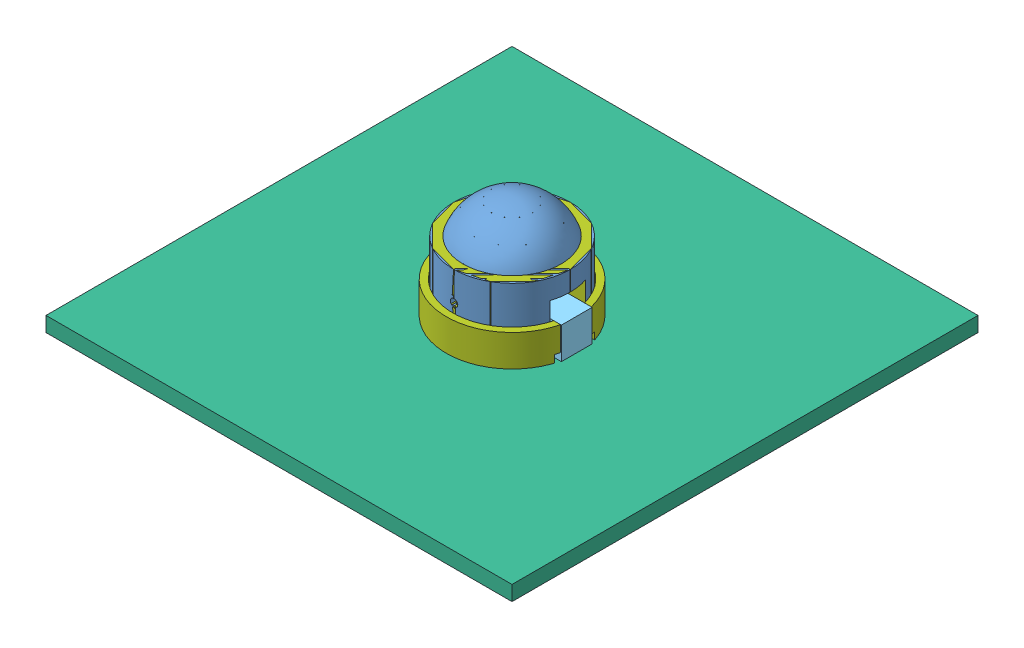
SolidWorks assembly Flippi, configuration Default. Lengths in mm.
Overall size (50 12.7 50).
8 component instances, 7 part files, 16 mates.
Components (placement in the parent):
- Lens-1: Lens [Default] at (3.3362 2.582 11.162) x (0.999999 0 -0.001341) z (0.001341 0 0.999999) size (12.5 8.3 12.5)
- Disk-1: Disk [Default] at (3.3362 4.082 11.162) x (-0.001341 0 -0.999999) z (-0.011796 -0.99993 0.000016) size (7.6 1.4 6.52)
- Axle-1: Axle [Default] at (3.3287 4.082 5.565) x (0.079368 -0.996845 -0.000106) z (-0.996844 -0.079368 0.001337) size (0.6 10 0.6)
- Foil-1: Foil [Default] at (6.9205 15.7806 -6.6241) x (-0.001341 0 -0.999999) z (-0.011796 -0.99993 0.000016) size (7.6 1.8 6.52)
- Coil-1: Coil [Default] at (-3.6145 -0.218 11.2307) size (4.7 3.4 3.3)
- PCB-1: PCB [Default] at (3.3276 -0.218 11.162) x (0 0 -1) z (-1 0 0) size (50 1.6 50)
- Coil-2: Coil [Default] at (5.5855 -0.218 11.2307) size (4.7 3.4 3.3)
- Support-1: Support [Default] at (34.5851 -1.1193 -2.8131) size (13.71 11.1 14.1)
Mates (geometry in assembly coordinates):
- Concentric1: concentric anti-aligned: cylinder of Lens-1 through (3.3278 4.082 4.912) axis (0.001341 0 0.999999) radius 0.4; cylinder of Axle-1 through (3.3421 4.082 15.565) axis (-0.001341 0 -0.999999) radius 0.3
- Concentric2: concentric aligned: cylinder of Disk-1 through (3.3409 4.082 14.712) axis (-0.001341 0 -0.999999) radius 0.35; cylinder of Axle-1 through (3.3421 4.082 15.565) axis (-0.001341 0 -0.999999) radius 0.3
- Coincident3: coincident anti-aligned: plane of Disk-1 through (3.8861 4.0755 11.1612) normal (0.99993 -0.011796 -0.001341); plane of Foil-1 through (3.8861 4.0755 11.1612) normal (-0.99993 0.011796 0.001341)
- Coincident4: coincident aligned: plane of Disk-1 through (2.4653 2.0922 13.1131) normal (-0.011796 -0.99993 0.000016); plane of Foil-1 through (4.2665 2.0709 14.0937) normal (-0.011796 -0.99993 0.000016)
- Coincident7: coincident aligned: circle of Disk-1; circle of Foil-1
- Distance1: distance = 0.05 mm aligned: plane of Disk-1 through (2.4539 1.1258 13.1131) normal (-0.001341 0 -0.999999); plane of Lens-1 through (13.3387 2.582 13.0485) normal (-0.001341 0 -0.999999)
- Coincident14: coincident anti-aligned: plane of Coil-1 through (-3.6145 -0.218 11.2307) normal (0 -1 0); plane of PCB-1 through (3.3276 -0.218 11.162) normal (0 1 0)
- Coincident16: coincident anti-aligned: line of Coil-1 through (-3.6224 -0.218 9.512) axis (0 0 1); line of PCB-1 through (-3.6224 -0.218 12.812) axis (0 0 -1)
- Coincident18: coincident aligned: line of Coil-1 through (-3.6224 -0.218 12.812) axis (1 0 0); line of PCB-1 through (-3.6224 -0.218 12.812) axis (1 0 0)
- Coincident19: coincident anti-aligned: plane of PCB-1 through (3.3276 -0.218 11.162) normal (0 1 0); plane of Coil-2 through (5.5855 -0.218 11.2307) normal (0 -1 0)
- Coincident20: coincident anti-aligned: line of PCB-1 through (10.2776 -0.218 12.812) axis (-1 0 0); line of Coil-2 through (5.5776 -0.218 12.812) axis (1 0 0)
- Coincident21: coincident aligned: line of PCB-1 through (10.2776 -0.218 12.812) axis (0 0 -1); line of Coil-2 through (10.2776 -0.218 12.812) axis (0 0 -1)
- Coincident24: coincident anti-aligned: plane of Lens-1 through (-0.5638 2.582 11.1672) normal (0 -1 0); plane of Support-1 through (3.3362 2.582 11.162) normal (0 1 0)
- Coincident25: coincident anti-aligned: plane of PCB-1 through (3.3276 -0.218 11.162) normal (0 1 0); plane of Support-1 through (3.3362 -0.218 11.162) normal (0 -1 0)
- Coincident26: coincident anti-aligned: plane of Coil-1 through (-3.6224 3.182 9.512) normal (0 0 -1); plane of Support-1 through (-3.518 -0.218 9.512) normal (0 0 1)
- Concentric4: concentric aligned: circle of Lens-1; circle of Support-1
